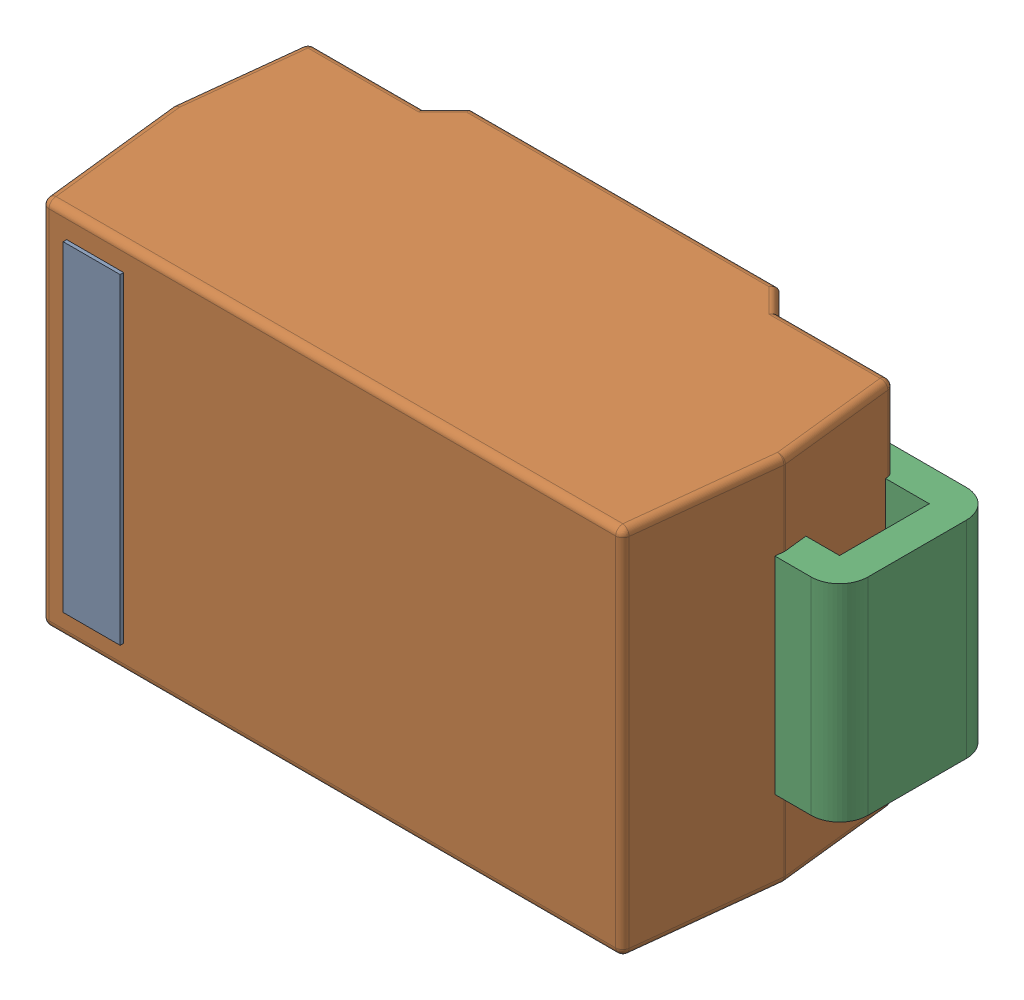
SolidWorks assembly SMA-DIODE_1, configuration Standard. Lengths in mm.
Overall size (5.2 2.6 2.08).
4 component instances, 4 part files, 0 mates.
Components (placement in the parent):
- Refdes-1: Refdes [Standard] at (0 0 -3.425) size (0.4 2.25 0.02)
- Body-1: Body [Standard] at (0 0 -3.425) size (4.3 2.6 2.06)
- Cathode-1: Cathode [Standard] at (0 0 -3.3) size (1.14 1.45 1.09)
- Anode-1: Anode [Standard] at (0 0 -3.3) size (1.14 1.45 1.09)
